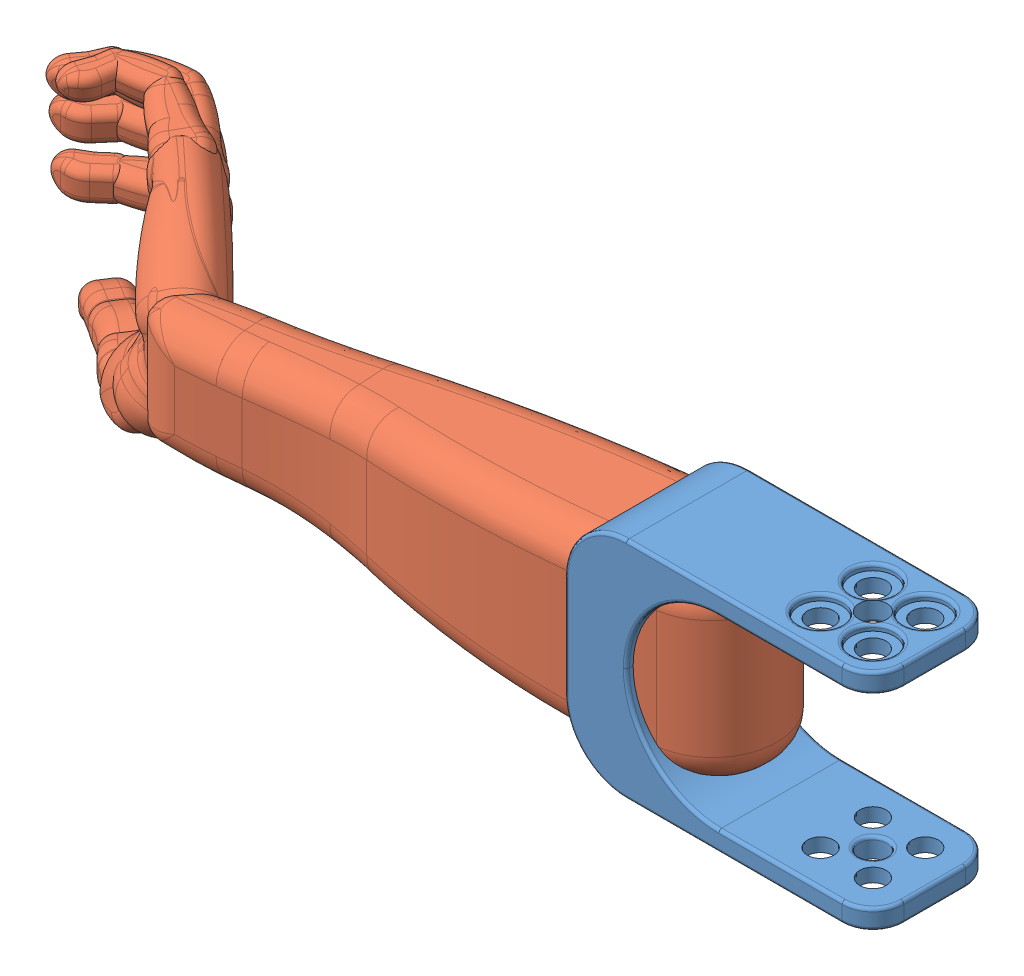
SolidWorks assembly Hand assembly, configuration Default. Lengths in mm.
Overall size (164.15 42.96 137.29).
2 component instances, 2 part files, 2 mates.
Components (placement in the parent):
- crawler elbow V2-1: crawler elbow V2 [Default] at origin size (50 36.68 20)
- Hand-2: Hand [Default] at (-69.8997 33.6127 4.2758) x (0 -1 0) z (0.709003 0 0.705205) size (42.96 86.64 112.66)
Mates (geometry in assembly coordinates):
- Parallel3: parallel aligned: line of crawler elbow V2-1 through (-5.2712 10 -5.3911) axis (0 1 0); line of Hand-2 through (4.4118 8.4056 -7.6441) axis (0 1 0)
- Parallel4: parallel anti-aligned: line of crawler elbow V2-1 through (-5.2712 26.4 14.6089) axis (0 -1 0); line of Hand-2 through (7.6306 8.3847 13.1043) axis (0 1 0)
